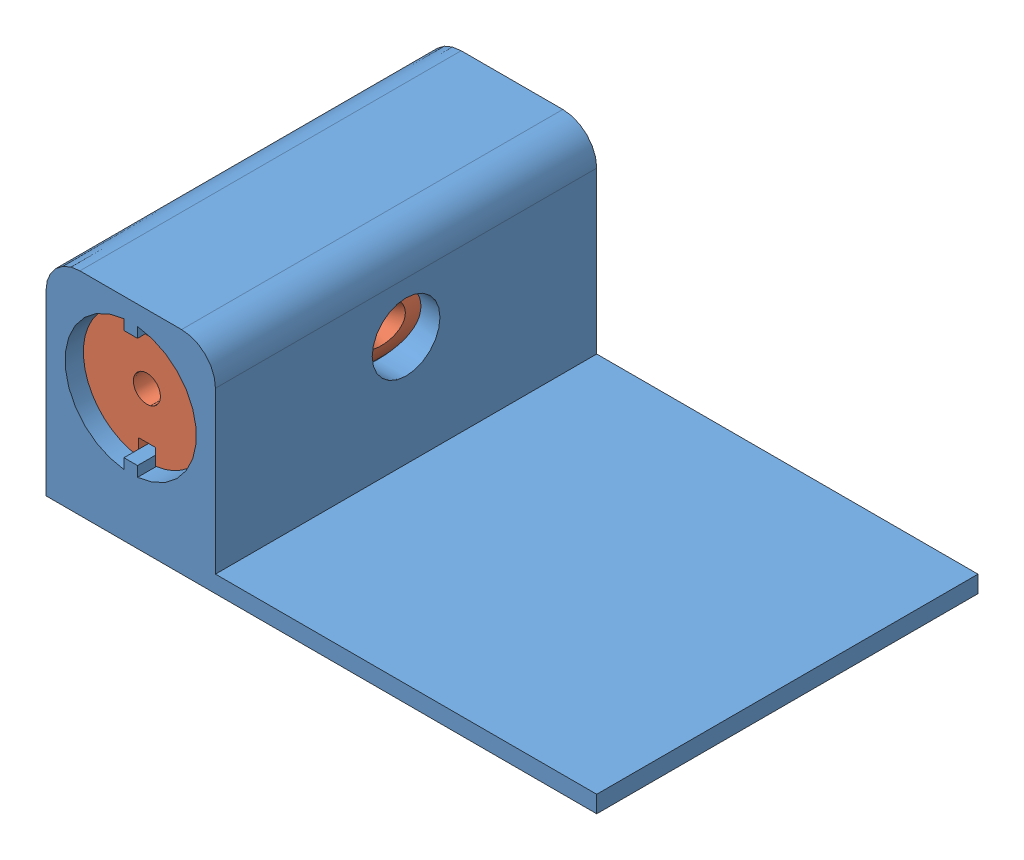
SolidWorks assembly Assemblage1, configuration Défaut. Lengths in mm.
Overall size (65 25 45).
2 component instances, 2 part files, 2 mates.
Components (placement in the parent):
- bati-1: bati [Défaut] at (17.699 3.0955 42.5) size (65 25 45)
- mobile v3-1: mobile v3 [Défaut] at (-21.2891 7.2938 55.5882) x (0 0 1) z (1 0 0) size (30 14.87 15)
Mates (geometry in assembly coordinates):
- Coaxiale1: concentric anti-aligned: circle of bati-1; cylinder of mobile v3-1 through (-21.2891 7.2938 85.5882) axis (0 0 -1) radius 7.5
- Parallèle2: parallel anti-aligned: plane of bati-1 through (-20.4891 -1.8974 42.5) normal (1 0 0); plane of mobile v3-1 through (-20.2891 -0.8924 55.5882) normal (-1 0 0)
